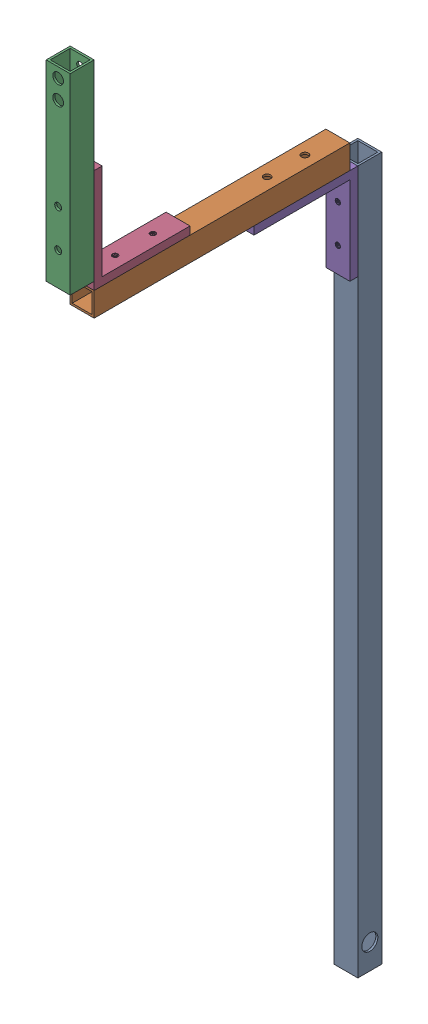
SolidWorks assembly ZBar, configuration Default. Lengths in mm.
Overall size (19.06 736.6 247.65).
5 component instances, 4 part files, 12 mates.
Components (placement in the parent):
- Tube3-1: Tube3 [Default] at (48.0566 -250.5437 144.8569) size (19.05 558.8 19.05)
- Tube2-1: Tube2 [Default] at (67.1166 327.3063 -407.5931) x (-1 0 0) z (0 1 0) size (19.05 203.2 19.05)
- Tube1-1: Tube1 [Default] at (67.1066 -428.3437 354.4069) x (-1 0 0) z (0 0 -1) size (19.05 152.4 19.05)
- ZBarBracket-1: ZBarBracket [Default] at (48.0666 327.3063 354.4069) x (0 1 0) z (-1 0 0) size (82.84 76.49 19.05)
- ZBarBracket-2: ZBarBracket [Default] at (67.1166 308.2563 144.8569) x (0 0 1) z (1 0 0) size (82.84 76.49 19.05)
Mates (geometry in assembly coordinates):
- Concentric1: concentric anti-aligned: cylinder of Tube3-1 through (57.5866 282.0563 144.8569) axis (0 0 -1) radius 2.75; circle of ZBarBracket-2
- Coincident2: coincident anti-aligned: plane of Tube3-1 through (48.0566 663.8563 144.8569) normal (0 0 1); plane of ZBarBracket-2 through (67.1166 308.2563 144.8569) normal (0 0 -1)
- Concentric2: concentric anti-aligned: cylinder of Tube2-1 through (57.5966 308.2563 177.4069) axis (0 1 0) radius 2.75; circle of ZBarBracket-2
- Coincident3: coincident anti-aligned: plane of Tube2-1 through (67.1166 308.2563 506.8069) normal (0 -1 0); plane of ZBarBracket-2 through (67.1166 308.2563 151.2069) normal (0 1 0)
- Concentric3: concentric aligned: cylinder of Tube2-1 through (57.5966 308.2563 298.2069) axis (0 1 0) radius 2.75; circle of ZBarBracket-1
- Coincident4: coincident anti-aligned: plane of Tube2-1 through (67.1166 327.3063 506.8069) normal (0 1 0); plane of ZBarBracket-1 through (48.0666 327.3063 354.4069) normal (0 -1 0)
- Concentric5: concentric anti-aligned: cylinder of Tube2-1 through (57.5966 308.2563 207.4069) axis (0 1 0) radius 2.75; circle of ZBarBracket-2
- Concentric6: concentric aligned: cylinder of Tube2-1 through (57.5966 308.2563 328.2069) axis (0 1 0) radius 2.75; circle of ZBarBracket-1
- Concentric7: concentric anti-aligned: cylinder of Tube3-1 through (57.5866 252.0563 144.8569) axis (0 0 -1) radius 2.75; circle of ZBarBracket-2
- Concentric8: concentric: cylinder of Tube1-1 through (57.5866 359.8563 373.4569) axis (0 0 -1) radius 2.75; circle of ZBarBracket-1
- Concentric9: concentric aligned: cylinder of Tube1-1 through (57.5866 389.8563 373.4569) axis (0 0 -1) radius 2.75; circle of ZBarBracket-1
- Coincident6: coincident: plane of Tube1-1 through (67.1066 486.0563 354.4069) normal (0 0 -1); plane of ZBarBracket-1 through (48.0666 333.6563 354.4069) normal (0 0 1)
